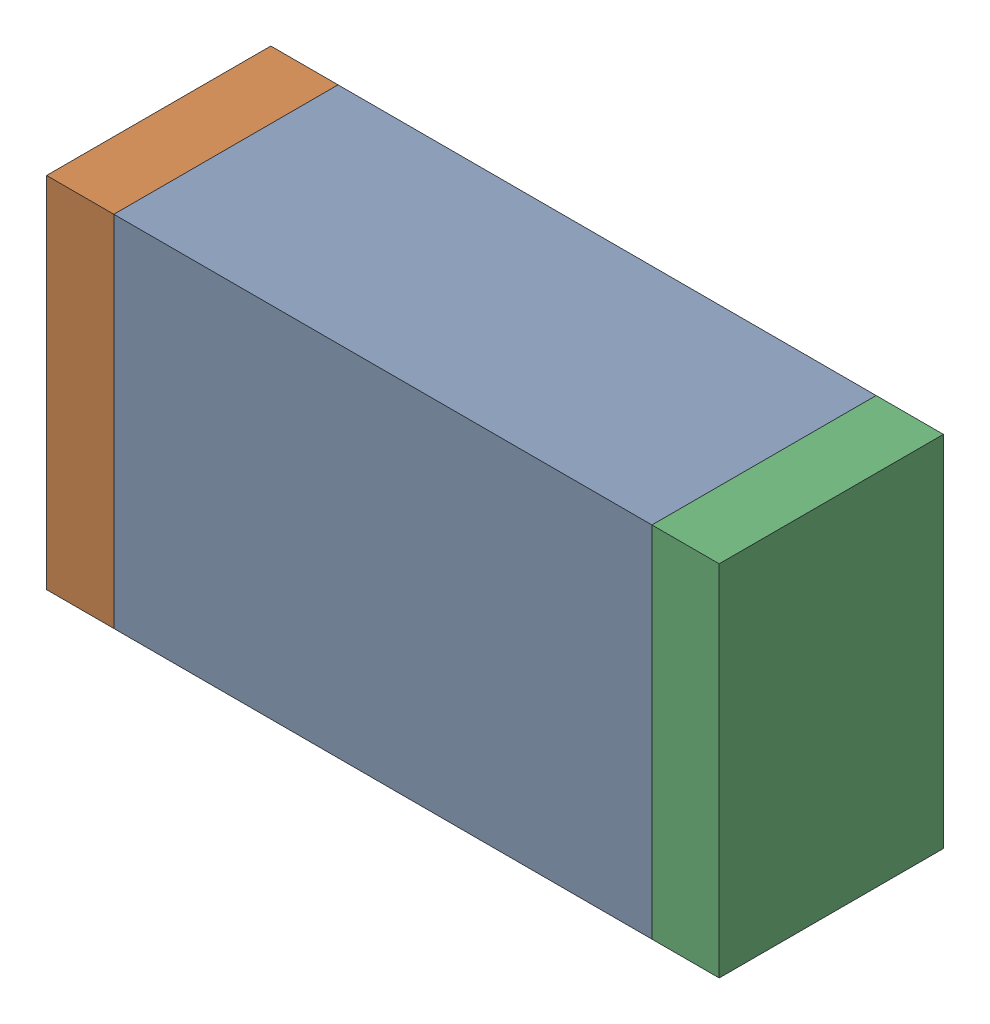
SolidWorks assembly C35, configuration Default. Lengths in mm.
Overall size (1.5 0.8 0.5).
6 component instances, 2 part files, 0 mates.
Components (placement in the parent):
- 836752368-1: 836752368 [Default] at (124.95 30.9 0) size (1.2 0.8 0.5)
  - Extruded-1: Extruded [Default] at origin size (1.2 0.8 0.5)
- 836752496-1: 836752496 [Default] at (124.275 30.9 0) size (0.15 0.8 0.5)
  - Extruded_2-1: Extruded_2 [Default] at origin size (0.15 0.8 0.5)
- 836752496-2: 836752496 [Default] at (125.625 30.9 0) size (0.15 0.8 0.5)
  - Extruded_2-1: Extruded_2 [Default] at origin size (0.15 0.8 0.5)
